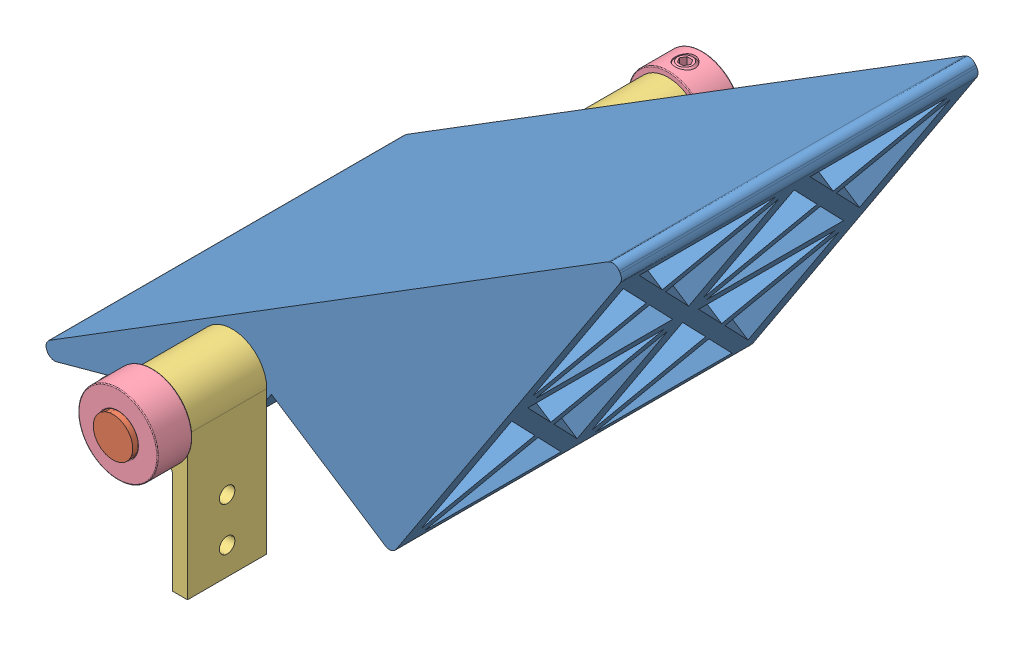
SolidWorks assembly ComponentAssembly, configuration Default. Lengths in mm.
Overall size (186.6 216.09 190.5).
6 component instances, 4 part files, 9 mates.
Components (placement in the parent):
- HingedWedge3DPrint-1: HingedWedge3DPrint [Default] at (169.27 200.7766 141.8841) x (0.54734 0.83691 0) z (0 0 1) size (196.37 94.54 114.3)
- Shaft-1: Shaft [Default] at (43.9387 113.5053 46.6341) x (0.780539 0.625107 0) z (0 0 1) size (12.7 12.7 190.5)
- AluminumPlate-1: AluminumPlate [Default] at (44.0657 113.5053 224.4341) x (0 -1 0) z (0 0 -1) size (56.97 22.1 25.4)
- AluminumPlate-2: AluminumPlate [Default] at (44.0657 113.5053 84.7341) x (0 -1 0) z (0 0 -1) size (56.97 22.1 25.4)
- 9946K150_SET SCREW SHAFT COLLAR-1: 9946K150_SET SCREW SHAFT COLLAR [9946K15] at (43.9387 113.5053 229.9903) x (0.473025 0.881049 0) z (0 0 1) size (25.4 25.4 11.11)
- 9946K150_SET SCREW SHAFT COLLAR-2: 9946K150_SET SCREW SHAFT COLLAR [9946K15] at (43.9387 113.5053 53.7778) size (25.4 25.4 11.11)
Mates (geometry in assembly coordinates):
- Coincident6: coincident: cylinder of Shaft-1 through (43.9387 113.5053 237.1341) axis (0 0 -1) radius 6.35; circle of AluminumPlate-1
- Coincident7: coincident: cylinder of Shaft-1 through (43.9387 113.5053 237.1341) axis (0 0 -1) radius 6.35; circle of AluminumPlate-2
- Concentric5: concentric: circle of Shaft-1; circle of 9946K150_SET SCREW SHAFT COLLAR-1
- Coincident10: coincident: plane of AluminumPlate-1 through (44.0657 113.5053 224.4341) normal (0 0 1); plane of 9946K150_SET SCREW SHAFT COLLAR-1 through (43.9387 113.5053 224.4341) normal (0 0 -1)
- Concentric6: concentric: circle of Shaft-1; circle of 9946K150_SET SCREW SHAFT COLLAR-2
- Coincident11: coincident: plane of AluminumPlate-2 through (44.0657 113.5053 59.3341) normal (0 0 -1); plane of 9946K150_SET SCREW SHAFT COLLAR-2 through (43.9387 113.5053 59.3341) normal (0 0 1)
- Width2: width: plane of Shaft-1 through (43.9387 113.5053 46.6341) normal (0 0 -1); plane of Shaft-1 through (43.9387 113.5053 237.1341) normal (0 0 1); plane of 9946K150_SET SCREW SHAFT COLLAR-1 through (43.9387 113.5053 235.5466) normal (0 0 1); plane of 9946K150_SET SCREW SHAFT COLLAR-2 through (43.9387 113.5053 48.2216) normal (0 0 -1)
- Width3: width: plane of Shaft-1 through (43.9387 113.5053 46.6341) normal (0 0 -1); plane of Shaft-1 through (43.9387 113.5053 237.1341) normal (0 0 1); plane of HingedWedge3DPrint-1 through (169.27 200.7766 199.0341) normal (0 0 1); plane of HingedWedge3DPrint-1 through (169.27 200.7766 84.7341) normal (0 0 -1)
- Concentric8: concentric: cylinder of HingedWedge3DPrint-1 through (43.9387 113.5053 84.7341) axis (0 0 1) radius 6.35; cylinder of Shaft-1 through (43.9387 113.5053 237.1341) axis (0 0 -1) radius 6.35
